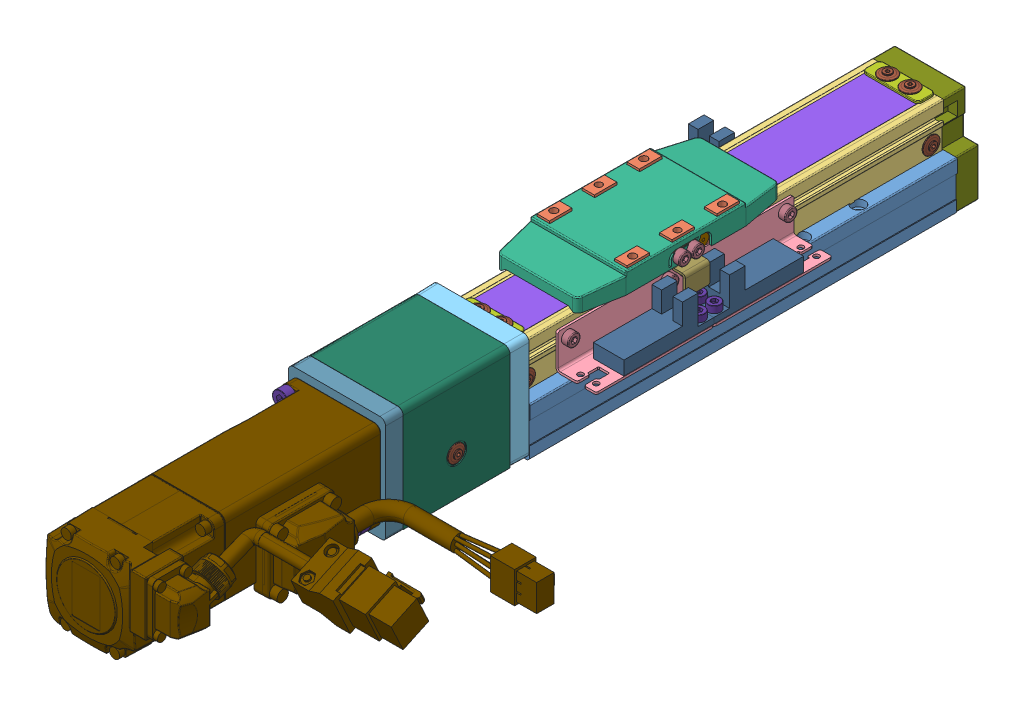
SolidWorks assembly G4-BC-100W, configuration 默认. Lengths in mm.
Overall size (137.38 57.84 375.76).
62 component instances, 19 part files, 51 mates.
Components (placement in the parent):
- 复件 底座GY4+140^G4-BC-100W-1: 复件 底座GY4+140^G4-BC-100W [默认] at (-6.4941 12.4482 0) x (-1 0 0) z (0 -1 0) size (44 190 22.05) (virtual)
- 复件 滑台G4^G4-BC-100W-1: 复件 滑台G4^G4-BC-100W [默认] at (2.1217 9 -70) x (-1 0 0) z (0 0 -1) size (40 11.99 50) (virtual)
- 复件 侧盖G4+140^G4-BC-100W-1: 复件 侧盖G4+140^G4-BC-100W [默认] at (5.1767 14.25 0) x (-1 0 0) z (0 0 -1) size (8.3 20.5 190) (virtual)
- 复件 台达100W电机ECMA-C20401GS^G4-BC-100W-1: 复件 台达100W电机ECMA-C20401GS^G4-BC-100W [默认] at (-9.9033 25 88.95) x (-1 0 0) z (0 1 0) size (117.31 104.21 58.85) (hidden, virtual)
- 复件 304开关座片G5-12^G4-BC-100W-1: 复件 304开关座片G5-12^G4-BC-100W [Default] at (5.9767 22.8 -17.5) x (0 0 -1) z (1 0 0) size (52.5 16 18) (virtual)
- 复件 丝杆座板GY4^G4-BC-100W-1: 复件 丝杆座板GY4^G4-BC-100W [默认] at (-9.9033 25 0) x (-1 0 0) z (0 0 -1) size (43 47.4 8.5) (virtual)
- 复件 滑台盖G4^G4-BC-100W-1: 复件 滑台盖G4^G4-BC-100W [默认] at (-9.9033 42.1 -115) x (0 0 1) z (0 -1 0) size (90 42.6 9) (virtual)
- 复件 304钢带压片G4^G4-BC-100W-1: 复件 304钢带压片G4^G4-BC-100W [默认] at (-9.9033 41.6 -186) x (-1 0 0) z (0 0 -1) size (25 1 8) (virtual)
- 复件 钢带G4+140^G4-BC-100W-1: 复件 钢带G4+140^G4-BC-100W [Default] at (-20.8433 41.5 -581.114) x (0 0 -1) z (0 1 0) size (190 23.5 0.1) (virtual)
- 复件 304钢带压片G4^G4-BC-100W-2: 复件 304钢带压片G4^G4-BC-100W [默认] at (-9.9033 41.6 -4) x (-1 0 0) z (0 0 -1) size (25 1 8) (virtual)
- 复件 弹子油杯D5x5.5^G4-BC-100W-1: 复件 弹子油杯D5x5.5^G4-BC-100W [默认] at (-30.3783 45.5 -78.5) x (0 0.72753 0.686076) z (1 0 0) size (5 5 5.73) (virtual)
- 复件 弹子油杯D5x5.5^G4-BC-100W-2: 复件 弹子油杯D5x5.5^G4-BC-100W [默认] at (10.6217 45.5 -78.5) x (0 0.972647 -0.232289) z (-1 0 0) size (5 5 5.73) (virtual)
- 复件 光电开关EE-SX674^G4-BC-100W-1: 复件 光电开关EE-SX674^G4-BC-100W [默认] at (10.1767 23.8 -30) x (0 0 -1) z (1 0 0) size (40 15.5 13.6) (virtual)
- 复件 不锈钢内六角定制螺丝M3X7^G4-BC-100W-1: 复件 不锈钢内六角定制螺丝M3X7^G4-BC-100W [默认] at (-4.9033 42.9733 -4) x (0.724639 0 -0.689128) z (0 -1 0) size (7.67 7.67 6.5) (virtual)
- 复件 不锈钢内六角定制螺丝M3X7^G4-BC-100W-2: 复件 不锈钢内六角定制螺丝M3X7^G4-BC-100W [默认] at (-14.9033 42.9733 -4) x (0.264221 0 -0.964462) z (0 -1 0) size (7.67 7.67 6.5) (virtual)
- 复件 不锈钢内六角定制螺丝M3X7^G4-BC-100W-3: 复件 不锈钢内六角定制螺丝M3X7^G4-BC-100W [默认] at (-4.9033 42.9733 -186) x (-0.045987 0 0.998942) z (0 -1 0) size (7.67 7.67 6.5) (virtual)
- 复件 不锈钢内六角定制螺丝M3X7^G4-BC-100W-4: 复件 不锈钢内六角定制螺丝M3X7^G4-BC-100W [默认] at (-14.9033 42.9733 -186) x (0.70866 0 0.705551) z (0 -1 0) size (7.67 7.67 6.5) (virtual)
- 复件 不锈钢内六角定制螺丝M3X7^G4-BC-100W-5: 复件 不锈钢内六角定制螺丝M3X7^G4-BC-100W [默认] at (5.55 26.15 -5) x (0 0.645926 0.7634) z (-1 0 0) size (7.67 7.67 6.5) (virtual)
- 复件 不锈钢内六角定制螺丝M3X7^G4-BC-100W-6: 复件 不锈钢内六角定制螺丝M3X7^G4-BC-100W [默认] at (5.55 26.15 -185) x (0 0.430934 0.902383) z (-1 0 0) size (7.67 7.67 6.5) (virtual)
- 复件 不锈钢内六角定制螺丝M3X7^G4-BC-100W-7: 复件 不锈钢内六角定制螺丝M3X7^G4-BC-100W [默认] at (-25.3602 26.15 -185) x (0 -0.999818 -0.019076) z (1 0 0) size (7.67 7.67 6.5) (virtual)
- 复件 不锈钢内六角定制螺丝M3X7^G4-BC-100W-8: 复件 不锈钢内六角定制螺丝M3X7^G4-BC-100W [默认] at (-25.3565 26.15 -5) x (0 -1 0) z (1 0 0) size (7.67 7.67 6.5) (virtual)
- 复件 304感应片G5^G4-BC-100W-1: 复件 304感应片G5^G4-BC-100W [默认] at (15.6217 33 -75.5) x (0 1 0) z (0 0 1) size (15 6.5 11) (virtual)
- hexagon socket head cap screws gb-32: hexagon socket head cap screws gb [GB_FASTENER_SCREWS_HSHCS M3X6-N] at (14.1217 45.5 -73) x (-1 0 0) z (0 -0.928252 -0.371951) size (9 5.5 5.5)
- 复件 电机座GY4-T40^G4-BC-100W-1: 复件 电机座GY4-T40^G4-BC-100W [Default] at (2.2402 15.3681 8.5) size (43.2 47 55.5) (virtual)
- 复件 联轴器盖GY4^G4-BC-100W-1: 复件 联轴器盖GY4^G4-BC-100W [Default] at (-10.4785 48 41.9538) x (1 0 0) z (0 1 0) size (43 47.5 46.5) (virtual)
- 复件 光电开关EE-SX674^G4-BC-100W-15: 复件 光电开关EE-SX674^G4-BC-100W [默认] at (23.7767 23.8 -110) x (0 0 1) z (-1 0 0) size (40 15.5 13.6) (virtual)
- 复件 304开关座片G5-12^G4-BC-100W-9: 复件 304开关座片G5-12^G4-BC-100W [Default] at (5.9767 22.8 -70) x (0 0 -1) z (1 0 0) size (52.5 16 18) (virtual)
- 复件 304开关座片G5-12^G4-BC-100W-6: 复件 304开关座片G5-12^G4-BC-100W [Default] at (5.9767 22.8 -87.5) x (0 0 -1) z (1 0 0) size (52.5 16 18) (hidden, virtual)
- 复件 轴承端盖G4(机加件)^G4-BC-100W-1: 复件 轴承端盖G4(机加件)^G4-BC-100W [默认] at (-9.9033 11.9 -190) x (0 0 -1) z (1 0 0) size (10 40.8 43) (virtual)
- hexagon socket head cap screws gb-33: hexagon socket head cap screws gb [GB_FASTENER_SCREWS_HSHCS M3X6-N] at (14.1217 45.5 -67) x (-1 0 0) z (0 -0.928252 -0.371951) size (9 5.5 5.5)
- hexagon socket head cap screws gb-34: hexagon socket head cap screws gb [GB_FASTENER_SCREWS_HSHCS M3X6-N] at (-33.8783 45.5 -73) x (1 0 0) z (0 0.928252 0.371951) size (9 5.5 5.5)
- hexagon socket head cap screws gb-35: hexagon socket head cap screws gb [GB_FASTENER_SCREWS_HSHCS M3X6-N] at (-33.8783 45.5 -67) x (1 0 0) z (0 0.928252 0.371951) size (9 5.5 5.5)
- 复件 侧盖G4+140^G4-BC-100W-5: 复件 侧盖G4+140^G4-BC-100W [默认] at (-24.9833 14.25 -190) size (8.3 20.5 190) (virtual)
- 复件 光电开关EE-SX674^G4-BC-100W-14: 复件 光电开关EE-SX674^G4-BC-100W [默认] at (10.1767 23.8 -100) x (0 0 -1) z (1 0 0) size (40 15.5 13.6) (hidden, virtual)
- 复件 光电开关EE-SX674^G4-BC-100W-16: 复件 光电开关EE-SX674^G4-BC-100W [默认] at (-43.5833 23.8 -100) x (0 0 -1) z (1 0 0) size (40 15.5 13.6) (virtual)
- 复件 304开关座片G5-12^G4-BC-100W-14: 复件 304开关座片G5-12^G4-BC-100W [Default] at (-25.7833 22.8 -140) x (0 0 1) z (-1 0 0) size (52.5 16 18) (virtual)
- 复件 304感应片G5^G4-BC-100W-4: 复件 304感应片G5^G4-BC-100W [默认] at (-35.3783 33 -64.5) x (0 1 0) z (0 0 -1) size (15 6.5 11) (virtual)
- 复件 不锈钢内六角定制螺丝M3X7^G4-BC-100W-9: 复件 不锈钢内六角定制螺丝M3X7^G4-BC-100W [默认] at (-31.2802 19 32.25) x (0 -0.999818 -0.019076) z (1 0 0) size (7.67 7.67 6.5) (virtual)
- 复件 不锈钢内六角定制螺丝M3X7^G4-BC-100W-10: 复件 不锈钢内六角定制螺丝M3X7^G4-BC-100W [默认] at (11.4736 19 32.25) x (0 0.999818 0.019076) z (-1 0 0) size (7.67 7.67 6.5) (virtual)
- hexagon socket head cap screws gb-36: hexagon socket head cap screws gb [GB_FASTENER_SCREWS_HSHCS M3X6-N] at (-26.4033 5.05 -199.6) x (0 0 1) z (-0.891634 -0.452757 0) size (9 5.5 5.5)
- hexagon socket head cap screws gb-37: hexagon socket head cap screws gb [GB_FASTENER_SCREWS_HSHCS M3X6-N] at (6.5967 5.05 -199.6) x (0 0 1) z (-0.891634 -0.452757 0) size (9 5.5 5.5)
- hexagon socket head cap screws gb-38: hexagon socket head cap screws gb [GB_FASTENER_SCREWS_HSHCS M3X6-N] at (-26.4033 18.05 -199.6) x (0 0 1) z (-0.891634 -0.452757 0) size (9 5.5 5.5)
- hexagon socket head cap screws gb-39: hexagon socket head cap screws gb [GB_FASTENER_SCREWS_HSHCS M3X6-N] at (6.5967 18.05 -199.6) x (0 0 1) z (-0.891634 -0.452757 0) size (9 5.5 5.5)
- hexagon socket head cap screws gb-41: hexagon socket head cap screws gb [GB_FASTENER_SCREWS_HSHCS M3X6-N] at (9.9767 34.8 -21.75) x (-1 0 0) z (0 -0.928252 -0.371951) size (9 5.5 5.5)
- hexagon socket head cap screws gb-42: hexagon socket head cap screws gb [GB_FASTENER_SCREWS_HSHCS M3X6-N] at (9.9767 34.8 -65.75) x (-1 0 0) z (0 -0.928252 -0.371951) size (9 5.5 5.5)
- hexagon socket head cap screws gb-43: hexagon socket head cap screws gb [GB_FASTENER_SCREWS_HSHCS M3X6-N] at (9.9767 34.8 -74.25) x (-1 0 0) z (0 0.928252 -0.371951) size (9 5.5 5.5)
- hexagon socket head cap screws gb-44: hexagon socket head cap screws gb [GB_FASTENER_SCREWS_HSHCS M3X6-N] at (9.9767 34.8 -118.25) x (-1 0 0) z (0 0.928252 -0.371951) size (9 5.5 5.5)
- hexagon socket head cap screws gb-45: hexagon socket head cap screws gb [GB_FASTENER_SCREWS_HSHCS M3X6-N] at (9.9767 34.8 -91.75) x (-1 0 0) z (0 -0.928252 -0.371951) size (9 5.5 5.5) (hidden)
- hexagon socket head cap screws gb-46: hexagon socket head cap screws gb [GB_FASTENER_SCREWS_HSHCS M3X6-N] at (9.9767 34.8 -135.75) x (-1 0 0) z (0 -0.928252 -0.371951) size (9 5.5 5.5) (hidden)
- hexagon socket head cap screws gb-47: hexagon socket head cap screws gb [GB_FASTENER_SCREWS_HSHCS M3X6-N] at (-29.7833 34.8 -135.75) x (1 0 0) z (0 0.928252 0.371951) size (9 5.5 5.5)
- hexagon socket head cap screws gb-48: hexagon socket head cap screws gb [GB_FASTENER_SCREWS_HSHCS M3X6-N] at (-29.7833 34.8 -91.75) x (1 0 0) z (0 0.928252 0.371951) size (9 5.5 5.5)
- socket head cap screw_iso-2: socket head cap screw_iso [ISO 4762 M3 x 5 --- 5N] at (13.4767 29.4 -66.5) x (0 -1 0) z (0 0 1) size (8 5.5 5.5)
- socket head cap screw_iso-3: socket head cap screw_iso [ISO 4762 M3 x 5 --- 5N] at (20.4767 29.4 -66.5) x (0 -1 0) z (0 0 1) size (8 5.5 5.5)
- socket head cap screw_iso-5: socket head cap screw_iso [ISO 4762 M4 x 12 --- 12N] at (6.3602 8.7365 73) x (0 0 -1) z (1 0 0) size (16 7 7)
- socket head cap screw_iso-6: socket head cap screw_iso [ISO 4762 M4 x 12 --- 12N] at (-26.1667 41.2635 73) x (0 0 -1) z (0.971713 0.236163 0) size (16 7 7)
- socket head cap screw_iso-7: socket head cap screw_iso [ISO 4762 M3 x 5 --- 5N] at (20.4767 29.4 -73.5) x (0 -1 0) z (0 0 1) size (8 5.5 5.5)
- socket head cap screw_iso-8: socket head cap screw_iso [ISO 4762 M3 x 5 --- 5N] at (13.4767 29.4 -73.5) x (0 -1 0) z (0 0 1) size (8 5.5 5.5)
- socket head cap screw_iso-9: socket head cap screw_iso [ISO 4762 M3 x 5 --- 5N] at (13.4767 29.4 -136.5) x (0 -1 0) z (0 0 1) size (8 5.5 5.5) (hidden)
- socket head cap screw_iso-10: socket head cap screw_iso [ISO 4762 M3 x 5 --- 5N] at (20.4767 29.4 -136.5) x (0 -1 0) z (0 0 1) size (8 5.5 5.5) (hidden)
- socket head cap screw_iso-11: socket head cap screw_iso [ISO 4762 M3 x 5 --- 5N] at (-33.2833 29.4 -136.5) x (0 -1 0) z (0 0 -1) size (8 5.5 5.5)
- socket head cap screw_iso-12: socket head cap screw_iso [ISO 4762 M3 x 5 --- 5N] at (-40.2833 29.4 -136.5) x (0 -1 0) z (0 0 -1) size (8 5.5 5.5)
- 复件 台达100W带刹车电机ECM-B3L-C20401SS1^G4-BC-100W-1: 复件 台达100W带刹车电机ECM-B3L-C20401SS1^G4-BC-100W [Default] at (-9.9033 25 69) x (0 1 0) z (0 0 -1) size (53.15 124.71 136.81) (virtual)
Mates (geometry in assembly coordinates):
- 重合86: coincident: plane of 复件 滑台G4^G4-BC-100W-1 through (-29.8783 50 -55) normal (0 1 0); plane of 复件 滑台盖G4^G4-BC-100W-1 through (-31.2033 50 -96.25) normal (0 -1 0)
- 同心50: concentric: cylinder of 复件 滑台G4^G4-BC-100W-1 through (-29.8783 45.5 -78.5) axis (-1 0 0) radius 2.5; cylinder of 复件 弹子油杯D5x5.5^G4-BC-100W-1 through (-24.8783 45.5 -78.5) axis (-1 0 0) radius 2.5
- 重合98: coincident: plane of 复件 滑台G4^G4-BC-100W-1 through (-24.8783 45.5 -78.5) normal (-1 0 0); circle of 复件 弹子油杯D5x5.5^G4-BC-100W-1
- 同心51: concentric: cylinder of 复件 滑台G4^G4-BC-100W-1 through (10.1217 45.5 -78.5) axis (1 0 0) radius 2.5; cylinder of 复件 弹子油杯D5x5.5^G4-BC-100W-2 through (5.1217 45.5 -78.5) axis (1 0 0) radius 2.5
- 重合99: coincident: plane of 复件 滑台G4^G4-BC-100W-1 through (5.1217 45.5 -78.5) normal (1 0 0); circle of 复件 弹子油杯D5x5.5^G4-BC-100W-2
- 重合127: coincident: plane of 复件 304钢带压片G4^G4-BC-100W-1 through (0.5967 42.6 -184) normal (0 1 0); circle of 复件 不锈钢内六角定制螺丝M3X7^G4-BC-100W-3
- 重合128: coincident: plane of 复件 304钢带压片G4^G4-BC-100W-1 through (0.5967 42.6 -184) normal (0 1 0); circle of 复件 不锈钢内六角定制螺丝M3X7^G4-BC-100W-4
- 同心86: concentric: circle of 复件 侧盖G4+140^G4-BC-100W-1; cylinder of 复件 不锈钢内六角定制螺丝M3X7^G4-BC-100W-6 through (0.07 26.15 -185) axis (1 0 0) radius 1.5
- 重合133: coincident: plane of 复件 侧盖G4+140^G4-BC-100W-1 through (5.1767 30.4257 -190) normal (1 0 0); circle of 复件 不锈钢内六角定制螺丝M3X7^G4-BC-100W-6
- 重合150: coincident: plane of 复件 滑台G4^G4-BC-100W-1 through (10.1217 42.5 -95) normal (1 0 0); plane of 复件 304感应片G5^G4-BC-100W-1 through (10.1217 41 -64.5) normal (-1 0 0)
- 同心103: concentric: cylinder of 复件 滑台G4^G4-BC-100W-1 through (10.1217 45.5 -73) axis (1 0 0) radius 1.25; cylinder of 复件 304感应片G5^G4-BC-100W-1 through (10.1217 45.5 -73) axis (-1 0 0) radius 1.7
- 同心104: concentric: cylinder of 复件 滑台G4^G4-BC-100W-1 through (10.1217 45.5 -67) axis (1 0 0) radius 1.25; cylinder of 复件 304感应片G5^G4-BC-100W-1 through (10.1217 45.5 -67) axis (-1 0 0) radius 1.7
- 同心105: concentric: cylinder of 复件 滑台G4^G4-BC-100W-1 through (10.1217 45.5 -73) axis (1 0 0) radius 1.25; cylinder of hexagon socket head cap screws gb-32 through (5.1217 45.5 -73) axis (1 0 0) radius 1.5
- 重合154: coincident: plane of 复件 304感应片G5^G4-BC-100W-1 through (11.1217 41 -64.5) normal (1 0 0); plane of hexagon socket head cap screws gb-32 through (11.1217 45.5 -73) normal (-1 0 0)
- 宽度8: width: plane of 复件 滑台盖G4^G4-BC-100W-1 through (-30.1033 42.1 -75.05) normal (0 0 1); plane of 复件 滑台盖G4^G4-BC-100W-1 through (-30.1033 42.1 -64.95) normal (0 0 -1); plane of 复件 滑台G4^G4-BC-100W-1 through (-29.8783 52 -65) normal (0 0 1); plane of 复件 滑台G4^G4-BC-100W-1 through (-29.8783 52 -75) normal (0 0 -1)
- 宽度9: width: plane of 复件 滑台G4^G4-BC-100W-1 through (-24.3783 48 -95) normal (1 0 0); plane of 复件 滑台G4^G4-BC-100W-1 through (-29.8783 52 -95) normal (-1 0 0); plane of 复件 滑台盖G4^G4-BC-100W-1 through (-24.1533 42.1 -64.95) normal (-1 0 0); plane of 复件 滑台盖G4^G4-BC-100W-1 through (-30.1033 50.6 -96.25) normal (1 0 0)
- 重合171: coincident: plane of 复件 底座GY4+140^G4-BC-100W-1 through (-31.4033 21.55 -190) normal (0 0 -1); plane of 复件 轴承端盖G4(机加件)^G4-BC-100W-1 through (-9.9033 11.9 -190) normal (0 0 1)
- 宽度10: width: plane of 复件 底座GY4+140^G4-BC-100W-1 through (12.0967 21.55 -190) normal (1 0 0); plane of 复件 底座GY4+140^G4-BC-100W-1 through (-31.9033 16.05 -190) normal (-1 0 0); plane of 复件 滑台盖G4^G4-BC-100W-1 through (-31.2033 50.6 -96.25) normal (-1 0 0); plane of 复件 滑台盖G4^G4-BC-100W-1 through (11.3967 50.6 -96.25) normal (1 0 0)
- 距离4: distance = 52 mm: plane of 复件 滑台G4^G4-BC-100W-1 through (-24.3783 52 -95) normal (0 1 0); plane of 复件 底座GY4+140^G4-BC-100W-1 through (15.1408 0 0) normal (0 -1 0)
- 重合187: coincident: plane of 复件 底座GY4+140^G4-BC-100W-1 through (-31.4033 6.05 -190) normal (-1 0 0); plane of 复件 轴承端盖G4(机加件)^G4-BC-100W-1 through (-31.4033 11.9 -200) normal (-1 0 0)
- 同心117: concentric: cylinder of 复件 不锈钢内六角定制螺丝M3X7^G4-BC-100W-7 through (-19.8802 26.15 -185) axis (-1 0 0) radius 1.5; cylinder of 复件 侧盖G4+140^G4-BC-100W-5 through (-24.9833 26.15 -185) axis (-1 0 0) radius 1.5
- 相切3: tangent: torus of 复件 不锈钢内六角定制螺丝M3X7^G4-BC-100W-7; plane of 复件 侧盖G4+140^G4-BC-100W-5 through (-24.9833 30.4257 0) normal (-1 0 0)
- 重合189: coincident: plane of 复件 304钢带压片G4^G4-BC-100W-1 through (0.5967 41.6 -184) normal (0 -1 0); plane of 复件 钢带G4+140^G4-BC-100W-1 through (-20.8433 41.6 -581.114) normal (0 1 0)
- 同心118: concentric: cylinder of 复件 304钢带压片G4^G4-BC-100W-1 through (-4.9033 42.6 -186) axis (0 -1 0) radius 1.65; cylinder of 复件 不锈钢内六角定制螺丝M3X7^G4-BC-100W-3 through (-4.9033 37.4933 -186) axis (0 1 0) radius 1.5
- 同心119: concentric: cylinder of 复件 304钢带压片G4^G4-BC-100W-1 through (-14.9033 42.6 -186) axis (0 -1 0) radius 1.65; cylinder of 复件 不锈钢内六角定制螺丝M3X7^G4-BC-100W-4 through (-14.9033 37.4933 -186) axis (0 1 0) radius 1.5
- 重合190: coincident: plane of 复件 304钢带压片G4^G4-BC-100W-1 through (0.5967 42.6 -190) normal (0 0 -1); plane of 复件 轴承端盖G4(机加件)^G4-BC-100W-1 through (-9.9033 11.9 -190) normal (0 0 1)
- 宽度11: width: plane of 复件 304钢带压片G4^G4-BC-100W-1 through (-22.4033 42.6 -184) normal (-1 0 0); plane of 复件 304钢带压片G4^G4-BC-100W-1 through (2.5967 42.6 -184) normal (1 0 0); plane of 复件 侧盖G4+140^G4-BC-100W-1 through (5.9767 41.05 -190) normal (1 0 0); plane of 复件 侧盖G4+140^G4-BC-100W-5 through (-25.7833 41.05 0) normal (-1 0 0)
- 同心120: concentric: cylinder of 复件 联轴器盖GY4^G4-BC-100W-1 through (-31.4033 19 32.25) axis (-1 0 0) radius 1.75; cylinder of 复件 不锈钢内六角定制螺丝M3X7^G4-BC-100W-9 through (-25.8002 19 32.25) axis (-1 0 0) radius 1.5
- 相切4: tangent: plane of 复件 联轴器盖GY4^G4-BC-100W-1 through (-30.9033 19 32.25) normal (-1 0 0); torus of 复件 不锈钢内六角定制螺丝M3X7^G4-BC-100W-9
- 重合191: coincident: plane of 复件 轴承端盖G4(机加件)^G4-BC-100W-1 through (-26.4033 6.75 -196.6) normal (0 0 -1); plane of hexagon socket head cap screws gb-36 through (-26.4033 5.05 -196.6) normal (0 0 1)
- 同心121: concentric: cylinder of 复件 轴承端盖G4(机加件)^G4-BC-100W-1 through (-26.4033 5.05 -200) axis (0 0 -1) radius 1.7; cylinder of hexagon socket head cap screws gb-36 through (-26.4033 5.05 -190.6) axis (0 0 -1) radius 1.5
- 重合193: coincident: plane of 复件 304开关座片G5-12^G4-BC-100W-1 through (6.9767 40.8 -70) normal (1 0 0); plane of hexagon socket head cap screws gb-41 through (6.9767 34.8 -21.75) normal (-1 0 0)
- 同心123: concentric: cylinder of 复件 304开关座片G5-12^G4-BC-100W-1 through (5.9767 34.8 -21.75) axis (1 0 0) radius 1.6; cylinder of hexagon socket head cap screws gb-41 through (0.9767 34.8 -21.75) axis (1 0 0) radius 1.5
- 同心126: concentric: cylinder of 复件 光电开关EE-SX674^G4-BC-100W-1 through (13.4767 12.8 -66.5) axis (0 1 0) radius 1.75; cylinder of socket head cap screw_iso-2 through (13.4767 61.15 -66.5) axis (0 1 0) radius 2.75
- 重合196: coincident: plane of 复件 光电开关EE-SX674^G4-BC-100W-1 through (23.7767 26.4 -63) normal (0 1 0); plane of socket head cap screw_iso-2 through (16.2267 26.4 -66.5) normal (0 -1 0)
- 同心127: concentric: cylinder of 复件 光电开关EE-SX674^G4-BC-100W-1 through (20.4767 12.8 -66.5) axis (0 1 0) radius 1.75; cylinder of socket head cap screw_iso-3 through (20.4767 61.15 -66.5) axis (0 1 0) radius 2.75
- 重合197: coincident: plane of 复件 光电开关EE-SX674^G4-BC-100W-1 through (23.7767 26.4 -63) normal (0 1 0); plane of socket head cap screw_iso-3 through (23.2267 26.4 -66.5) normal (0 -1 0)
- 重合198: coincident: plane of 复件 台达100W电机ECMA-C20401GS^G4-BC-100W-1 through (10.2538 13.0581 69) normal (0 0 1); plane of socket head cap screw_iso-5 through (6.3602 12.2365 69) normal (0 0 -1)
- 重合199: coincident: plane of 复件 台达100W电机ECMA-C20401GS^G4-BC-100W-1 through (-21.8452 45.1571 69) normal (0 0 1); plane of socket head cap screw_iso-6 through (-26.9933 44.6645 69) normal (0 0 -1)
- 同心128: concentric: cone of 复件 台达100W电机ECMA-C20401GS^G4-BC-100W-1 through (-26.1667 41.2635 69) axis (0 0 1); cylinder of socket head cap screw_iso-6 through (-26.1667 41.2635 104.75) axis (0 0 1) radius 2
- 同心129: concentric: cone of 复件 台达100W电机ECMA-C20401GS^G4-BC-100W-1 through (6.3602 8.7365 69) axis (0 0 1); cylinder of socket head cap screw_iso-5 through (6.3602 8.7365 104.75) axis (0 0 1) radius 3.5
- 宽度12: width: plane of 复件 光电开关EE-SX674^G4-BC-100W-15 through (10.1767 39.3 -77) normal (0 0 1); plane of 复件 光电开关EE-SX674^G4-BC-100W-1 through (23.7767 39.3 -63) normal (0 0 -1); plane of 复件 304感应片G5^G4-BC-100W-1 through (11.1217 42.5 -75.5) normal (0 0 -1); plane of 复件 304感应片G5^G4-BC-100W-1 through (16.6217 40.5 -64.5) normal (0 0 1)
- 同心130: concentric: cylinder of 复件 304开关座片G5-12^G4-BC-100W-1 through (13.4767 23.8 -66.5) axis (0 1 0) radius 1.25; cylinder of socket head cap screw_iso-2 through (13.4767 61.15 -66.5) axis (0 1 0) radius 2.75
- 同心131: concentric: cylinder of 复件 304开关座片G5-12^G4-BC-100W-1 through (20.4767 23.8 -66.5) axis (0 1 0) radius 1.25; cylinder of socket head cap screw_iso-3 through (20.4767 61.15 -66.5) axis (0 1 0) radius 1.5
- 重合200: coincident: plane of 复件 304开关座片G5-12^G4-BC-100W-1 through (7.9767 23.8 -70) normal (0 1 0); plane of 复件 光电开关EE-SX674^G4-BC-100W-1 through (23.7767 23.8 -70) normal (0 -1 0)
- 重合201: coincident: plane of 复件 侧盖G4+140^G4-BC-100W-1 through (5.9767 32.95 -190) normal (1 0 0); plane of 复件 304开关座片G5-12^G4-BC-100W-9 through (5.9767 24.8 -122.5) normal (-1 0 0)
- 宽度13: width: plane of 复件 侧盖G4+140^G4-BC-100W-1 through (5.9767 36.55 -190) normal (0 -1 0); plane of 复件 侧盖G4+140^G4-BC-100W-1 through (5.0767 33.05 -190) normal (0 1 0); cylinder of hexagon socket head cap screws gb-44 through (0.9767 34.8 -118.25) axis (1 0 0) radius 1.5
- 距离5: distance = 134 mm: line of 复件 光电开关EE-SX674^G4-BC-100W-1 through (23.7767 26.4 -70) axis (-1 0 0); plane of 复件 电机座GY4-T40^G4-BC-100W-1 through (2.2402 15.3681 64) normal (0 0 1)
- 同心132: concentric: cylinder of 复件 台达100W电机ECMA-C20401GS^G4-BC-100W-1 through (-9.9033 25 39.5) axis (0 0 1) radius 4; cylinder of 复件 台达100W带刹车电机ECM-B3L-C20401SS1^G4-BC-100W-1 through (-9.9033 25 59.4) axis (0 0 -1) radius 4
- 重合203: coincident: plane of 复件 电机座GY4-T40^G4-BC-100W-1 through (2.2402 15.3681 64) normal (0 0 1); plane of 复件 台达100W带刹车电机ECM-B3L-C20401SS1^G4-BC-100W-1 through (-29.9233 4.98 64) normal (0 0 -1)
- 同心133: concentric: cylinder of socket head cap screw_iso-6 through (-26.1667 41.2635 104.75) axis (0 0 1) radius 3.5; cone of 复件 台达100W带刹车电机ECM-B3L-C20401SS1^G4-BC-100W-1 through (-26.1667 41.2635 69) axis (0 0 1)
